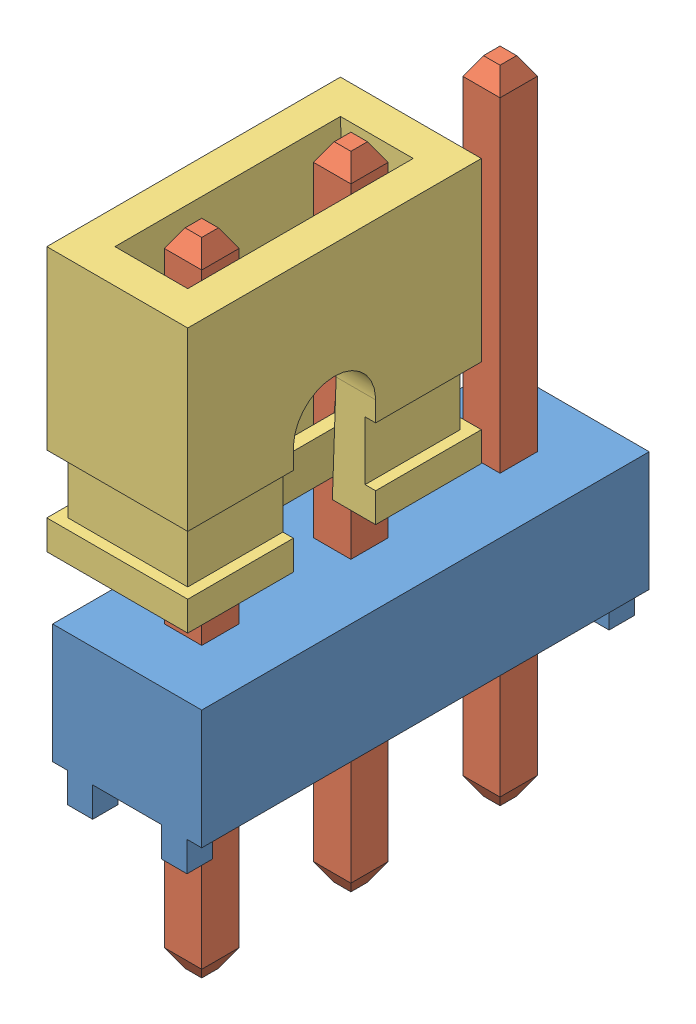
SolidWorks assembly Assem3, configuration Default. Lengths in mm.
Overall size (2.54 10.92 7.84).
4 component instances, 3 part files, 0 mates.
Components (placement in the parent):
- JP-3p-Coheader.stp-1: JP-3p-Coheader.stp [Default] at (-58.6411 17.5414 18.533) size (2.54 10.92 7.62)
  - TSW-101-07-S-T_body.stp-1: TSW-101-07-S-T_body.stp [Default] at origin size (2.54 2.54 7.62)
  - T-1S6-07-TSW-1-07-1-T.stp-1: T-1S6-07-TSW-1-07-1-T.stp [Default] at (0 -2.54 0) size (0.89 10.92 5.97)
- DauchupJumper.stp-2: DauchupJumper.stp [Default] at (-58.5925 23.5642 20.0601) x (0 0 1) z (0 1 0) size (5 2.4 4.5)
